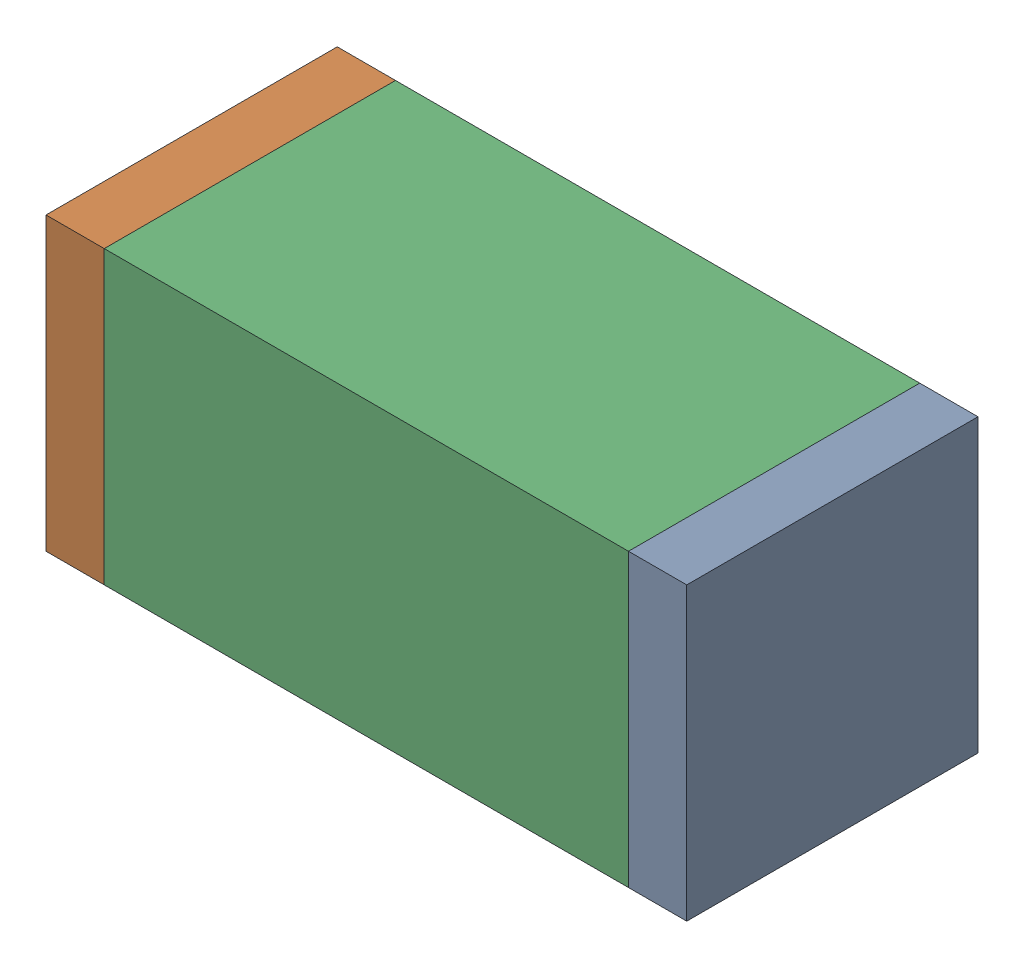
SolidWorks assembly C13, configuration Default. Lengths in mm.
Overall size (1.1 0.5 0.5).
6 component instances, 2 part files, 0 mates.
Components (placement in the parent):
- 810156080-1: 810156080 [Default] at (107.35 11.45 0) size (0.1 0.5 0.5)
  - Extruded_5-1: Extruded_5 [Default] at origin size (0.1 0.5 0.5)
- 810156080-2: 810156080 [Default] at (106.35 11.45 0) size (0.1 0.5 0.5)
  - Extruded_5-1: Extruded_5 [Default] at origin size (0.1 0.5 0.5)
- 836749680-1: 836749680 [Default] at (106.85 11.45 0) size (0.9 0.5 0.5)
  - Extruded_4-1: Extruded_4 [Default] at origin size (0.9 0.5 0.5)
